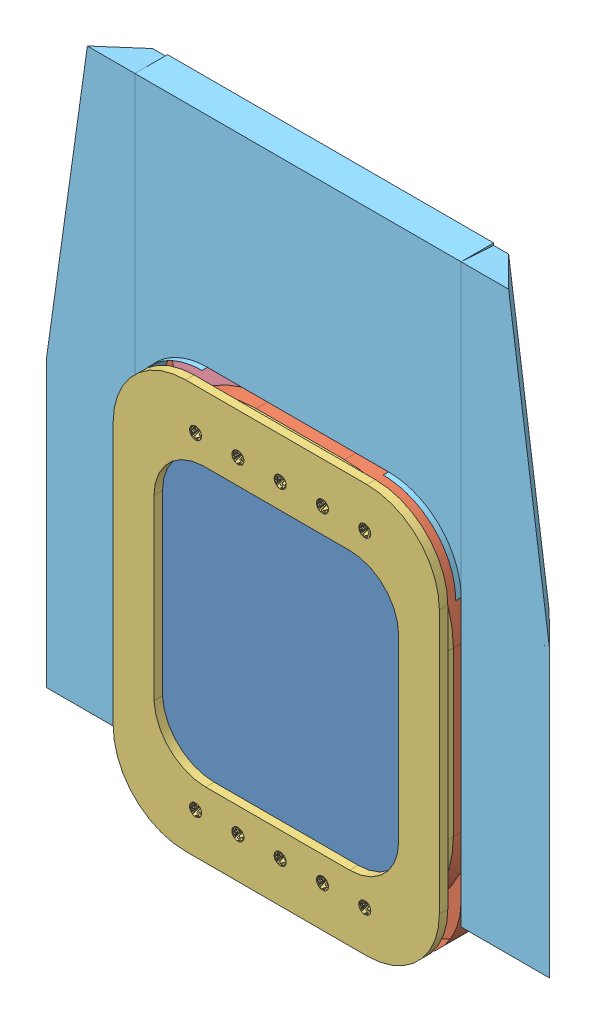
SolidWorks assembly Window As, configuration Default. Lengths in mm.
Overall size (528.81 658.71 63.76).
6 component instances, 6 part files, 16 mates.
Components (placement in the parent):
- Window, Normal-1: Window, Normal [Default] at (-192.0812 -28.7605 -12.5188) size (303.99 343.6 6.35)
- Part2 (2)-1: Part2 (2) [Default] at (-193.4544 -38.9205 -45.5388) size (342.9 429.26 40.89)
- Front Frame-1: Front Frame [Default] at (135.4543 -38.9205 11.6112) x (-1 0 0) z (0 0 -1) size (342.9 429.26 32.01)
- Window closer-1: Window closer [Default<As Machined>] at (134.081 232.3515 -21.4088) x (-1 0 0) z (0 0 -1) size (303.99 343.6 21.59)
- Cover-1: Cover [Default] at origin size (528.81 605.62 40)
- Part9^Window As-1: Part9^Window As [Default] at (-193.4544 -38.9205 -45.5388) x (-1 0 0) z (0 0 -1) (virtual)
Mates (geometry in assembly coordinates):
- Width1: width anti-aligned: plane of Window, Normal-1 through (122.9952 67.8688 2.7212) normal (1 0 0); plane of Front Frame-1 through (-180.9953 -42.0462 2.7212) normal (-1 0 0); plane of Window, Normal-1 through (120.9245 -28.6512 2.7212) normal (-1 0 0); plane of Front Frame-1 through (-178.9246 -28.6512 2.7212) normal (1 0 0)
- Coincident1: coincident anti-aligned: plane of Window, Normal-1 through (6.1552 184.7088 2.7212) normal (0 1 0); plane of Front Frame-1 through (-64.6246 184.7088 2.7212) normal (0 -1 0)
- Coincident2: coincident anti-aligned: plane of Window, Normal-1 through (6.1552 67.8688 2.7212) normal (0 0 1); plane of Front Frame-1 through (-64.6246 70.4088 2.7212) normal (0 0 -1)
- Width2: width anti-aligned: plane of Window closer-1 through (-180.9953 328.9808 -36.6488) normal (-1 0 0); plane of Part2 (2)-1 through (122.9952 219.0658 -36.6488) normal (1 0 0); plane of Window closer-1 through (-178.9246 235.5088 -36.6488) normal (1 0 0); plane of Part2 (2)-1 through (120.9245 235.5088 -36.6488) normal (-1 0 0)
- Parallel2: parallel aligned: line of Part2 (2)-1 through (99.5239 113.7576 -30.2988) axis (0 -1 0); line of Window closer-1 through (122.9952 328.9808 -30.2988) axis (0 -1 0)
- Coincident14: coincident anti-aligned: plane of Part2 (2)-1 through (-193.4544 -38.9205 -30.2988) normal (0 0 -1); plane of Window closer-1 through (-64.1553 328.9808 -30.2988) normal (0 0 1)
- LimitDistance1: limit distance = 279.4 mm: line of Window closer-1 through (-64.1553 445.8208 -36.6488) axis (1 0 0); line of Part2 (2)-1 through (-106.2161 166.4208 -36.6488) axis (1 0 0)
- Coincident15: coincident anti-aligned: plane of Part2 (2)-1 through (-193.4544 -38.9205 -13.7888) normal (0 0 1); plane of Front Frame-1 through (135.4543 -38.9205 -13.7888) normal (0 0 -1)
- Coincident17: coincident anti-aligned: line of Part2 (2)-1 through (131.7819 106.6639 -13.7888) axis (0 -1 0); line of Front Frame-1 through (131.7819 -64.9062 -13.7888) axis (0 1 0)
- Coincident18: coincident anti-aligned: line of Part2 (2)-1 through (-75.4821 220.9639 -13.7888) axis (1 0 0); line of Front Frame-1 through (17.4819 220.9639 -13.7888) axis (-1 0 0)
- Coincident19: coincident anti-aligned: line of Part2 (2)-1 through (-200.4501 159.3088 -11.2488) axis (0 0 -1); line of Cover-1 through (-200.4501 159.3088 -45.5388) axis (0 0 1)
- Coincident20: coincident: line of Part2 (2)-1 through (-124.2501 235.5088 -45.5388) axis (1 0 0); plane of Cover-1 through (0 0 -45.5388) normal (0 0 1)
- InPlace1: in place: plane of Part2 (2)-1 through (-193.4544 -38.9205 -45.5388) normal (0 0 -1); plane of ? through (0 0 -45.5388) normal (0 0 -1); moOrthogonalPlaneRef_w of Part2 (2)-1 through (-193.4544 -38.9205 -45.5388) normal (0 0 -1); plane of ? through (0 0 -45.5388) normal (0 1 0); plane of Part2 (2)-1 through (-193.4544 -38.9205 -45.5388) normal (0 0 -1); plane of ? through (0 0 -45.5388) normal (-1 0 0); plane of Part2 (2)-1 through (-193.4544 -38.9205 -45.5388) normal (0 0 -1); unknown of Part9^Window As-1
- Coincident21: coincident aligned: plane of assembly through (-193.4544 -38.9205 -45.5388) normal (0 0 -1); plane of assembly through (-193.4544 -38.9205 -45.5388) normal (0 0 -1)
- Coincident22: coincident aligned: moOrthogonalPlaneRef_w of Part2 (2)-1 through (-193.4544 -38.9205 -45.5388) normal (0 1 0); plane of Part9^Window As-1 through (-193.4544 -38.9205 -45.5388) normal (0 1 0)
- Coincident23: coincident anti-aligned: moOrthogonalPlaneRef_w of Part2 (2)-1 through (-193.4544 -38.9205 -45.5388) normal (1 0 0); plane of Part9^Window As-1 through (-193.4544 -38.9205 -45.5388) normal (-1 0 0)
